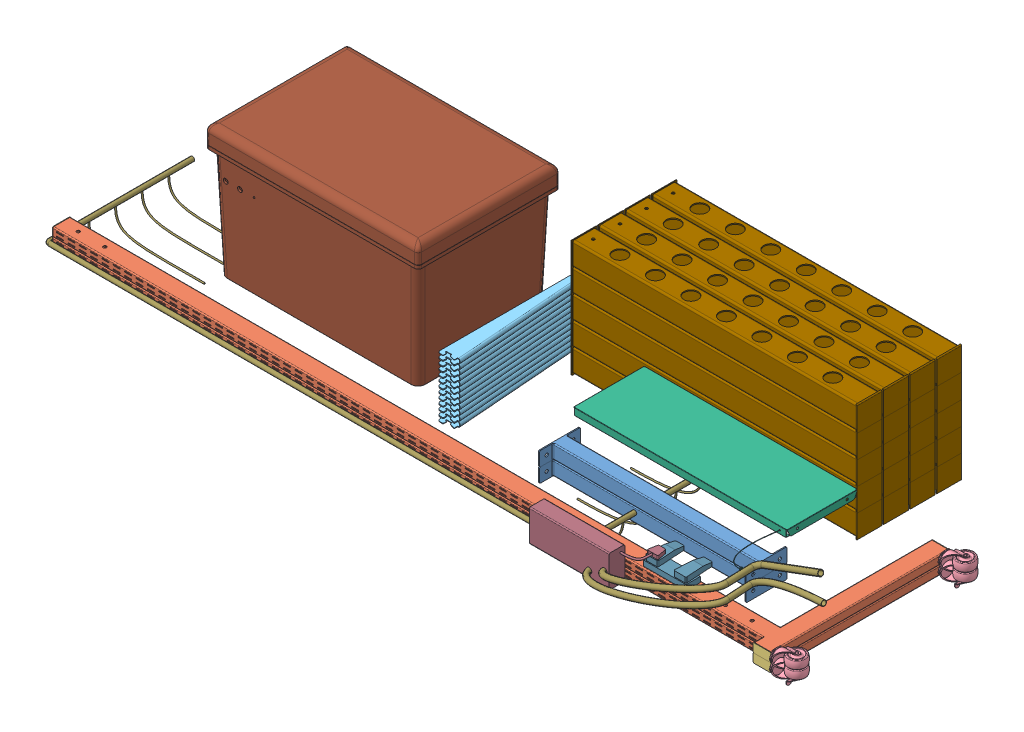
SolidWorks assembly Flat packed, configuration Default. Lengths in mm.
Overall size (2127.7 436.46 799.47).
91 component instances, 17 part files, 246 mates.
Components (placement in the parent):
- TB-600-1: TB-600 [Default] at (652.9227 60 -160.6207) x (-1 0 0) z (0 -1 0) size (585 115 40)
- TB-600-2: TB-600 [Default] at (652.9227 20 -160.6207) x (1 0 0) z (0 -1 0) size (585 115 40)
- TSU-F-L-P-1: TSU-F-L-P [Default] at (1094.8939 31 -50) x (0 1 0) z (0 0 1) size (25 2050 500)
- TSU-F-L-P-2: TSU-F-L-P [Default] at (1094.8939 6 -50) x (0 1 0) z (0 0 1) size (25 2050 500)
- TSU-CAP-1: TSU-CAP [Default] at (1094.7939 5.9 -64.9) x (0 -1 0) z (0 0 -1) size (25.2 50.2 6.5)
- TSU-CAP-2: TSU-CAP [Default] at (1094.7939 30.9 -64.9) x (0 -1 0) z (0 0 -1) size (25.2 50.2 6.5)
- TSU-CAP-3: TSU-CAP [Default] at (-495.0061 31.1 -50.1) x (0 1 0) z (-1 0 0) size (25.2 50.2 6.5)
- TSU-CAP-4: TSU-CAP [Default] at (1094.7939 30.9 -385.1) x (0 1 0) z (0 0 1) size (25.2 50.2 6.5)
- TSU-CAP-5: TSU-CAP [Default] at (-495.0061 6.1 -50.1) x (0 1 0) z (-1 0 0) size (25.2 50.2 6.5)
- TSU-CAP-6: TSU-CAP [Default] at (1094.7939 6.1 -385.1) x (0 1 0) z (0 0 1) size (25.2 50.2 6.5)
- 2834T320_THREADED-STEM SWIVEL CASTER-1: 2834T320_THREADED-STEM SWIVEL CASTER [2834T32] at (1125.8439 31 -462.5) x (0 0 -1) z (0 1 0) size (67.73 101.87 56.07)
- 2834T320_THREADED-STEM SWIVEL CASTER-2: 2834T320_THREADED-STEM SWIVEL CASTER [2834T32] at (1125.8439 6 12.5) x (0 0 -1) z (0 1 0) size (67.73 101.87 56.07)
- 2834T320_THREADED-STEM SWIVEL CASTER-3: 2834T320_THREADED-STEM SWIVEL CASTER [2834T32] at (1125.8439 31 12.5) x (0 0 -1) z (0 1 0) size (67.73 101.87 56.07)
- 2834T320_THREADED-STEM SWIVEL CASTER-4: 2834T320_THREADED-STEM SWIVEL CASTER [2834T32] at (1125.8439 6 -462.5) x (0 0 -1) z (0 1 0) size (67.73 101.87 56.07)
- TSS-600-1: TSS-600 [Default] at (644.4227 20 -318.1207) size (607 37.13 331.17) (hidden)
- TSUB-1: TSUB [Default] at (101.9538 119 -140.6207) x (0 -1 0) z (0 0 -1) size (14.07 50.86 484.03)
- TSUB-2: TSUB [Default] at (101.9538 63 -140.6207) x (0 -1 0) z (0 0 -1) size (14.07 50.86 484.03)
- TSUB-3: TSUB [Default] at (101.9538 77 -140.6207) x (0 -1 0) z (0 0 -1) size (14.07 50.86 484.03)
- TSUB-4: TSUB [Default] at (101.9538 49 -140.6207) x (0 -1 0) z (0 0 -1) size (14.07 50.86 484.03)
- TSS-600-2: TSS-600 [Default] at (644.4227 40 -318.1207) size (607 37.13 331.17) (hidden)
- TSUB-5: TSUB [Default] at (101.9538 147 -140.6207) x (0 -1 0) z (0 0 -1) size (14.07 50.86 484.03)
- TSUB-6: TSUB [Default] at (101.9538 133 -140.6207) x (0 -1 0) z (0 0 -1) size (14.07 50.86 484.03)
- TSS-600-3: TSS-600 [Default] at (644.4227 80 -318.1207) size (607 37.13 331.17) (hidden)
- TSUB-7: TSUB [Default] at (101.9538 7 -140.6207) x (0 -1 0) z (0 0 -1) size (14.07 50.86 484.03)
- TSUB-8: TSUB [Default] at (101.9538 91 -140.6207) x (0 -1 0) z (0 0 -1) size (14.07 50.86 484.03)
- TSS-600-4: TSS-600 [Default] at (644.4227 120 -318.1207) size (607 37.13 331.17)
- TSUB-9: TSUB [Default] at (101.9538 21 -140.6207) x (0 -1 0) z (0 0 -1) size (14.07 50.86 484.03)
- TSUB-10: TSUB [Default] at (101.9538 35 -140.6207) x (0 -1 0) z (0 0 -1) size (14.07 50.86 484.03)
- TSS-600-5: TSS-600 [Default] at (644.4227 60 -318.1207) size (607 37.13 331.17) (hidden)
- TSUB-11: TSUB [Default] at (101.9538 -7 -140.6207) x (0 -1 0) z (0 0 -1) size (14.07 50.86 484.03)
- TSUB-12: TSUB [Default] at (101.9538 105 -140.6207) x (0 -1 0) z (0 0 -1) size (14.07 50.86 484.03)
- TSS-600-6: TSS-600 [Default] at (644.4227 100 -318.1207) size (607 37.13 331.17) (hidden)
- hex bolt gradeab2_bsi-10: hex bolt gradeab2_bsi [BS EN 28765 - M8x1 x 45 x 22-N] at (-858.6061 48.8 -25) x (0 -1 0) z (0.924225 0 -0.381849) size (50.3 15.01 13) (hidden)
- hex bolt gradeab2_bsi-11: hex bolt gradeab2_bsi [BS EN 28765 - M8x1 x 45 x 22-N] at (-783.6061 48.8 -25) x (0 -1 0) z (0.999974 0 0.007224) size (50.3 15.01 13) (hidden)
- hex bolt gradeab2_bsi-12: hex bolt gradeab2_bsi [BS EN 28765 - M8x1 x 45 x 22-N] at (-322.8 60 -198.1207) size (50.3 15.01 13)
- hex bolt gradeab2_bsi-13: hex bolt gradeab2_bsi [BS EN 28765 - M8x1 x 45 x 22-N] at (-322.8 60 -123.1207) size (50.3 15.01 13) (hidden)
- hex bolt gradeab2_bsi-14: hex bolt gradeab2_bsi [BS EN 28765 - M8x1 x 45 x 22-N] at (-322.8 20 -198.1207) size (50.3 15.01 13)
- hex bolt gradeab2_bsi-15: hex bolt gradeab2_bsi [BS EN 28765 - M8x1 x 45 x 22-N] at (-322.8 20 -123.1207) size (50.3 15.01 13) (hidden)
- hex bolt gradeab2_bsi-16: hex bolt gradeab2_bsi [BS EN 28765 - M8x1 x 45 x 22-N] at (1040.3939 48.8 -25) x (0 -1 0) z (-0.924225 0 0.381849) size (50.3 15.01 13) (hidden)
- hex bolt gradeab2_bsi-17: hex bolt gradeab2_bsi [BS EN 28765 - M8x1 x 45 x 22-N] at (856.3064 20 -123.1207) x (-1 0 0) z (0 -0.924225 -0.381849) size (50.3 15.01 13) (hidden)
- hex nut gradec_bsi-1: hex nut gradec_bsi [BS EN 24034 - M8 - N] at (383.6 2067 -25) x (0 0 1) z (-1 0 0) size (13 15.01 7.9) (hidden)
- hex nut gradec_bsi-2: hex nut gradec_bsi [BS EN 24034 - M8 - N] at (383.6 1992 -25) x (0 0 1) z (-1 0 0) size (13 15.01 7.9) (hidden)
- hex nut gradec_bsi-3: hex nut gradec_bsi [BS EN 24034 - M8 - N] at (251.9064 60 -198.1207) x (0 0 -1) z (1 0 0) size (13 15.01 7.9) (hidden)
- hex nut gradec_bsi-4: hex nut gradec_bsi [BS EN 24034 - M8 - N] at (251.9064 60 -123.1207) x (0 0.383049 0.923728) z (1 0 0) size (13 15.01 7.9) (hidden)
- hex nut gradec_bsi-5: hex nut gradec_bsi [BS EN 24034 - M8 - N] at (-281.6 20 -123.1207) x (0 0 -1) z (1 0 0) size (13 15.01 7.9) (hidden)
- hex nut gradec_bsi-6: hex nut gradec_bsi [BS EN 24034 - M8 - N] at (281.6 20 -123.1207) x (0 0 1) z (-1 0 0) size (13 15.01 7.9) (hidden)
- hex nut gradec_bsi-7: hex nut gradec_bsi [BS EN 24034 - M8 - N] at (281.6 168 -25) x (0 0 1) z (-1 0 0) size (13 15.01 7.9) (hidden)
- hex nut gradec_bsi-8: hex nut gradec_bsi [BS EN 24034 - M8 - N] at (-281.6 20 -198.1207) x (0 0 -1) z (1 0 0) size (13 15.01 7.9)
- GB-600-b-1: GB-600-b [Default] at (542.4227 97.5 -600.6207) size (806 70 70)
- GB-600-p-1: GB-600-p [Default] at (0 1106.5 -2988.6404) size (92 218.31 4) (hidden)
- GB-600-p-2: GB-600-p [Default] at (542.4227 1106.5 -675.6207) size (92 218.31 4) (hidden)
- GB-600-b-2: GB-600-b [Default] at (542.4227 97.5 -675.6207) size (806 70 70)
- GB-600-p-3: GB-600-p [Default] at (542.4227 97.5 -450.6207) size (92 218.31 4) (hidden)
- GB-600-b-3: GB-600-b [Default] at (542.4227 97.5 -450.6207) size (806 70 70)
- GB-600-p-4: GB-600-p [Default] at (542.4227 97.5 -525.6207) size (92 218.31 4) (hidden)
- GB-600-b-4: GB-600-b [Default] at (542.4227 97.5 -525.6207) size (806 70 70)
- GB-600-b-5: GB-600-b [Default] at (542.4227 32.5 -450.6207) size (806 70 70)
- GB-600-b-6: GB-600-b [Default] at (542.4227 32.5 -525.6207) size (806 70 70)
- GB-600-b-7: GB-600-b [Default] at (542.4227 32.5 -600.6207) size (806 70 70)
- GB-600-b-8: GB-600-b [Default] at (542.4227 32.5 -675.6207) size (806 70 70)
- GB-600-b-9: GB-600-b [Default] at (542.4227 227.5 -450.6207) size (806 70 70)
- GB-600-b-10: GB-600-b [Default] at (542.4227 227.5 -525.6207) size (806 70 70)
- GB-600-b-11: GB-600-b [Default] at (542.4227 227.5 -600.6207) size (806 70 70)
- GB-600-b-12: GB-600-b [Default] at (542.4227 227.5 -675.6207) size (806 70 70)
- GB-600-p-5: GB-600-p [Default] at (542.4227 227.5 -450.6207) size (92 218.31 4)
- GB-600-p-6: GB-600-p [Default] at (542.4227 227.5 -525.6207) size (92 218.31 4)
- GB-600-p-7: GB-600-p [Default] at (542.4227 227.5 -600.6207) size (92 218.31 4)
- GB-600-p-8: GB-600-p [Default] at (542.4227 227.5 -675.6207) size (92 218.31 4)
- GB-600-p-9: GB-600-p [Default] at (542.4227 1171.5 -675.6207) size (92 218.31 4) (hidden)
- GB-600-p-10: GB-600-p [Default] at (0 1171.5 -2988.6404) size (92 218.31 4) (hidden)
- GB-600-p-11: GB-600-p [Default] at (542.4227 162.5 -525.6207) size (92 218.31 4) (hidden)
- GB-600-p-12: GB-600-p [Default] at (542.4227 162.5 -450.6207) size (92 218.31 4) (hidden)
- GB-600-b-13: GB-600-b [Default] at (542.4227 162.5 -675.6207) size (806 70 70)
- GB-600-b-14: GB-600-b [Default] at (542.4227 162.5 -600.6207) size (806 70 70)
- GB-600-b-15: GB-600-b [Default] at (542.4227 162.5 -525.6207) size (806 70 70)
- GB-600-b-16: GB-600-b [Default] at (542.4227 162.5 -450.6207) size (806 70 70)
- GB-600-p-13: GB-600-p [Default] at (542.4227 292.5 -675.6207) size (92 218.31 4)
- GB-600-p-14: GB-600-p [Default] at (542.4227 292.5 -600.6207) size (92 218.31 4)
- GB-600-p-15: GB-600-p [Default] at (542.4227 292.5 -525.6207) size (92 218.31 4)
- GB-600-p-16: GB-600-p [Default] at (542.4227 292.5 -450.6207) size (92 218.31 4)
- GB-600-b-17: GB-600-b [Default] at (542.4227 292.5 -450.6207) size (806 70 70)
- GB-600-b-18: GB-600-b [Default] at (542.4227 292.5 -525.6207) size (806 70 70)
- GB-600-b-19: GB-600-b [Default] at (542.4227 292.5 -600.6207) size (806 70 70)
- GB-600-b-20: GB-600-b [Default] at (542.4227 292.5 -675.6207) size (806 70 70)
- Part3-1: Part3 [Default] at (-318.2694 320 -342.4034) size (600 370 400)
- Part4-1: Part4 [Default] at origin
- Part5-1: Part5 [Default] at (1094.8939 6 0) x (0 1 0) z (0 0 1) size (241.4 2067.5 489.85)
- Part1-1: Part1 [Default] at (644.4227 82.8692 -318.1207) x (-1 0 0) z (0 -1 0) size (2 2 1357) (hidden)
- Part2-1: Part2 [Default] at (1094.8939 31 -50) x (0 0 -1) z (0 1 0) size (82.56 307.09 97.63)
- ele-1: ele [Default] at (-318.2694 5 -342.4034) x (1 0 0) z (0 1 0) size (624.24 196.22 364.08) (hidden)
- power brick-1: power brick [Default] at (1094.8939 43.5 -50) x (0 0 -1) z (0 1 0) size (82.62 120 30)
Mates (geometry in assembly coordinates):
- Concentric5: concentric anti-aligned: cylinder of TSU-F-L-P-1 through (1094.8939 31 -462.5) axis (1 0 0) radius 5.1; cylinder of 2834T320_THREADED-STEM SWIVEL CASTER-1 through (1106.7939 31 -462.5) axis (-1 0 0) radius 4.7625
- Coincident8: coincident anti-aligned: plane of TSU-F-L-P-1 through (1144.8939 31 -475) normal (1 0 0); plane of 2834T320_THREADED-STEM SWIVEL CASTER-1 through (1144.8939 31 -446.3957) normal (-1 0 0)
- Concentric9: concentric anti-aligned: cylinder of TSU-F-L-P-2 through (1094.8939 6 -462.5) axis (1 0 0) radius 5.1; cylinder of 2834T320_THREADED-STEM SWIVEL CASTER-4 through (1106.7939 6 -462.5) axis (-1 0 0) radius 4.7625
- Parallel4: parallel aligned: plane of TSU-F-L-P-1 through (-905.1061 43.5 -47) normal (0 1 0); plane of 2834T320_THREADED-STEM SWIVEL CASTER-1 through (1161.1023 42.9062 -483.1375) normal (0 1 0)
- Coincident16: coincident anti-aligned: plane of TSU-F-L-P-2 through (1144.8939 6 -475) normal (1 0 0); plane of 2834T320_THREADED-STEM SWIVEL CASTER-4 through (1144.8939 6 -446.3957) normal (-1 0 0)
- Concentric12: concentric anti-aligned: cylinder of TSU-F-L-P-1 through (1094.8939 31 12.5) axis (1 0 0) radius 5.1; cylinder of 2834T320_THREADED-STEM SWIVEL CASTER-3 through (1106.7939 31 12.5) axis (-1 0 0) radius 4.7625
- Coincident17: coincident anti-aligned: plane of TSU-F-L-P-1 through (1144.8939 31 -475) normal (1 0 0); plane of 2834T320_THREADED-STEM SWIVEL CASTER-3 through (1144.8939 31 28.6043) normal (-1 0 0)
- Coincident18: coincident aligned: plane of 2834T320_THREADED-STEM SWIVEL CASTER-1 through (1161.1023 42.9062 -483.1375) normal (0 1 0); plane of 2834T320_THREADED-STEM SWIVEL CASTER-3 through (1161.1023 42.9062 -8.1375) normal (0 1 0)
- Concentric13: concentric anti-aligned: cylinder of TSU-F-L-P-2 through (1094.8939 6 12.5) axis (1 0 0) radius 5.1; cylinder of 2834T320_THREADED-STEM SWIVEL CASTER-2 through (1106.7939 6 12.5) axis (-1 0 0) radius 4.7625
- Coincident19: coincident anti-aligned: plane of TSU-F-L-P-2 through (1144.8939 6 -475) normal (1 0 0); plane of 2834T320_THREADED-STEM SWIVEL CASTER-2 through (1144.8939 6 28.6043) normal (-1 0 0)
- Parallel6: parallel aligned: plane of TSU-F-L-P-2 through (-905.1061 -6.5 -47) normal (0 -1 0); plane of 2834T320_THREADED-STEM SWIVEL CASTER-2 through (1161.1023 -5.9062 -8.1375) normal (0 -1 0)
- Coincident21: coincident anti-aligned: plane of TSU-F-L-P-1 through (-905.1061 20 -25) normal (0 1 0); plane of TSU-CAP-4 through (1094.7939 20 20) normal (0 -1 0)
- Coincident22: coincident anti-aligned: plane of TSU-F-L-P-1 through (1096.3939 40.5 -475) normal (1 0 0); plane of TSU-CAP-4 through (1096.3939 30.9 20) normal (-1 0 0)
- Coincident23: coincident anti-aligned: plane of TSU-F-L-P-1 through (1097.8939 40.5 25) normal (0 0 1); plane of TSU-CAP-4 through (1094.7939 30.9 25) normal (0 0 -1)
- Coincident24: coincident anti-aligned: plane of TSU-F-L-P-2 through (-905.1061 17 -25) normal (0 -1 0); plane of TSU-CAP-6 through (1094.7939 17 20) normal (0 1 0)
- Coincident25: coincident anti-aligned: plane of TSU-F-L-P-2 through (1096.3939 15.5 -475) normal (1 0 0); plane of TSU-CAP-6 through (1096.3939 6.1 20) normal (-1 0 0)
- Coincident26: coincident anti-aligned: plane of TSU-F-L-P-2 through (1097.8939 15.5 25) normal (0 0 1); plane of TSU-CAP-6 through (1094.7939 6.1 25) normal (0 0 -1)
- Coincident27: coincident anti-aligned: plane of TSU-F-L-P-1 through (-905.1061 20 -25) normal (0 1 0); plane of TSU-CAP-2 through (1094.7939 20 -470) normal (0 -1 0)
- Coincident28: coincident anti-aligned: plane of TSU-F-L-P-1 through (1096.3939 40.5 -475) normal (1 0 0); plane of TSU-CAP-2 through (1096.3939 30.9 -470) normal (-1 0 0)
- Coincident29: coincident anti-aligned: plane of TSU-F-L-P-1 through (1097.8939 40.5 -475) normal (0 0 -1); plane of TSU-CAP-2 through (1094.7939 30.9 -475) normal (0 0 1)
- Coincident30: coincident anti-aligned: plane of TSU-F-L-P-2 through (-905.1061 -5 -25) normal (0 1 0); plane of TSU-CAP-1 through (1094.7939 -5 -470) normal (0 -1 0)
- Coincident31: coincident anti-aligned: plane of TSU-F-L-P-2 through (1096.3939 15.5 -475) normal (1 0 0); plane of TSU-CAP-1 through (1096.3939 5.9 -470) normal (-1 0 0)
- Coincident32: coincident anti-aligned: plane of TSU-F-L-P-2 through (1097.8939 15.5 -475) normal (0 0 -1); plane of TSU-CAP-1 through (1094.7939 5.9 -475) normal (0 0 1)
- Coincident33: coincident anti-aligned: plane of TSU-F-L-P-1 through (-905.1061 42 -25) normal (0 -1 0); plane of TSU-CAP-3 through (-900.1061 42 -50.1) normal (0 1 0)
- Coincident34: coincident anti-aligned: plane of TSU-F-L-P-1 through (-905.1061 40.5 -48.5) normal (0 0 1); plane of TSU-CAP-3 through (-900.1061 31.1 -48.5) normal (0 0 -1)
- Coincident35: coincident anti-aligned: plane of TSU-F-L-P-1 through (-905.1061 40.5 -47) normal (-1 0 0); plane of TSU-CAP-3 through (-905.1061 31.1 -50.1) normal (1 0 0)
- Coincident36: coincident anti-aligned: plane of TSU-F-L-P-2 through (-905.1061 17 -25) normal (0 -1 0); plane of TSU-CAP-5 through (-900.1061 17 -50.1) normal (0 1 0)
- Coincident37: coincident anti-aligned: plane of TSU-F-L-P-2 through (-905.1061 15.5 -48.5) normal (0 0 1); plane of TSU-CAP-5 through (-900.1061 6.1 -48.5) normal (0 0 -1)
- Coincident38: coincident anti-aligned: plane of TSU-F-L-P-2 through (-905.1061 15.5 -47) normal (-1 0 0); plane of TSU-CAP-5 through (-905.1061 6.1 -50.1) normal (1 0 0)
- Parallel7: parallel aligned: plane of TSU-F-L-P-2 through (-905.1061 18.5 -47) normal (0 1 0); plane of 2834T320_THREADED-STEM SWIVEL CASTER-4 through (1161.1023 17.9062 -483.1375) normal (0 1 0)
- Coincident90: coincident aligned: plane of TSS-600-4 through (945.4227 120 -418.1207) normal (0 0 -1); plane of TSS-600-6 through (945.4227 100 -418.1207) normal (0 0 -1)
- Coincident91: coincident aligned: plane of TSS-600-3 through (945.4227 80 -418.1207) normal (0 0 -1); plane of TSS-600-6 through (945.4227 100 -418.1207) normal (0 0 -1)
- Coincident93: coincident aligned: plane of TSS-600-3 through (945.4227 80 -418.1207) normal (0 0 -1); plane of TSS-600-5 through (945.4227 60 -418.1207) normal (0 0 -1)
- Coincident94: coincident aligned: plane of TSS-600-2 through (945.4227 40 -418.1207) normal (0 0 -1); plane of TSS-600-5 through (945.4227 60 -418.1207) normal (0 0 -1)
- Coincident95: coincident aligned: plane of TSS-600-1 through (945.4227 20 -418.1207) normal (0 0 -1); plane of TSS-600-2 through (945.4227 40 -418.1207) normal (0 0 -1)
- Concentric15: concentric: cylinder of TSU-F-L-P-1 through (-858.6061 18.5 -25) axis (0 1 0) radius 4.5; cylinder of hex bolt gradeab2_bsi-10 through (-858.6061 48.8 -25) axis (0 1 0) radius 4
- Coincident181: coincident: plane of TSU-F-L-P-1 through (-905.1061 43.5 -47) normal (0 1 0); plane of hex bolt gradeab2_bsi-10 through (-861.4721 43.5 -31.9368) normal (0 -1 0)
- Concentric16: concentric: cylinder of TSU-F-L-P-1 through (-783.6061 18.5 -25) axis (0 1 0) radius 4.5; cylinder of hex bolt gradeab2_bsi-11 through (-783.6061 48.8 -25) axis (0 1 0) radius 4
- Coincident182: coincident: plane of TSU-F-L-P-1 through (-905.1061 43.5 -47) normal (0 1 0); plane of hex bolt gradeab2_bsi-11 through (-783.5518 43.5 -32.5054) normal (0 -1 0)
- Concentric17: concentric: cylinder of TB-600-1 through (945.4227 60 -198.1207) axis (-1 0 0) radius 4.5; cylinder of hex bolt gradeab2_bsi-12 through (-322.8 60 -198.1207) axis (-1 0 0) radius 4
- Coincident183: coincident: plane of TSU-F-L-P-2 through (-905.1061 -6.5 -47) normal (0 -1 0); plane of hex bolt gradeab2_bsi-12 through (-317.5 67.5056 -198.1207) normal (1 0 0)
- Concentric18: concentric: cylinder of TB-600-1 through (945.4227 60 -123.1207) axis (-1 0 0) radius 4.5; cylinder of hex bolt gradeab2_bsi-13 through (-322.8 60 -123.1207) axis (-1 0 0) radius 4
- Coincident184: coincident: plane of TSU-F-L-P-2 through (-905.1061 -6.5 -47) normal (0 -1 0); plane of hex bolt gradeab2_bsi-13 through (-317.5 67.5056 -123.1207) normal (1 0 0)
- Concentric19: concentric: cylinder of TB-600-2 through (360.4227 20 -123.1207) axis (1 0 0) radius 4.5; cylinder of hex bolt gradeab2_bsi-15 through (-322.8 20 -123.1207) axis (-1 0 0) radius 4
- Coincident185: coincident: plane of TSU-F-L-P-2 through (-905.1061 -6.5 -47) normal (0 -1 0); plane of hex bolt gradeab2_bsi-15 through (-317.5 27.5056 -123.1207) normal (1 0 0)
- Concentric20: concentric: cylinder of TB-600-2 through (360.4227 20 -198.1207) axis (1 0 0) radius 4.5; cylinder of hex bolt gradeab2_bsi-14 through (-322.8 20 -198.1207) axis (-1 0 0) radius 4
- Coincident186: coincident: plane of TSU-F-L-P-2 through (-905.1061 -6.5 -47) normal (0 -1 0); plane of hex bolt gradeab2_bsi-14 through (-317.5 27.5056 -198.1207) normal (1 0 0)
- Concentric21: concentric: cylinder of TB-600-2 through (945.4227 20 -123.1207) axis (-1 0 0) radius 4.5; cylinder of hex bolt gradeab2_bsi-17 through (856.3064 20 -123.1207) axis (1 0 0) radius 4
- Coincident187: coincident: plane of TSU-F-L-P-1 through (-905.1061 43.5 -47) normal (0 1 0); plane of hex bolt gradeab2_bsi-17 through (851.0064 22.866 -130.0575) normal (-1 0 0)
- Concentric22: concentric: cylinder of TSU-F-L-P-1 through (1040.3939 16.9 -25) axis (0 1 0) radius 4.5; cylinder of hex bolt gradeab2_bsi-16 through (1040.3939 48.8 -25) axis (0 1 0) radius 4
- Coincident188: coincident: plane of TSU-F-L-P-1 through (-905.1061 43.5 -47) normal (0 1 0); plane of hex bolt gradeab2_bsi-16 through (1043.2599 43.5 -18.0632) normal (0 -1 0)
- Concentric23: concentric: cylinder of hex bolt gradeab2_bsi-10 through (-858.6061 48.8 -25) axis (0 1 0) radius 4; cylinder of hex nut gradec_bsi-1 through (391.5 2067 -25) axis (-1 0 0) radius 3.4
- Coincident189: coincident: plane of TB-600-1 through (363.4227 60 -160.6207) normal (1 0 0); plane of hex nut gradec_bsi-1 through (391.5 2074.5056 -25) normal (1 0 0)
- Concentric24: concentric: cylinder of hex bolt gradeab2_bsi-11 through (-783.6061 48.8 -25) axis (0 1 0) radius 4; cylinder of hex nut gradec_bsi-2 through (391.5 1992 -25) axis (-1 0 0) radius 3.4
- Coincident190: coincident: plane of TB-600-1 through (363.4227 60 -160.6207) normal (1 0 0); plane of hex nut gradec_bsi-2 through (391.5 1999.5056 -25) normal (1 0 0)
- Concentric25: concentric: cylinder of hex bolt gradeab2_bsi-12 through (-322.8 60 -198.1207) axis (-1 0 0) radius 4; cylinder of hex nut gradec_bsi-3 through (244.0064 60 -198.1207) axis (1 0 0) radius 3.4
- Coincident191: coincident: plane of TB-600-1 through (942.4227 60 -160.6207) normal (-1 0 0); plane of hex nut gradec_bsi-3 through (244.0064 67.5056 -198.1207) normal (-1 0 0)
- Concentric26: concentric: cylinder of hex bolt gradeab2_bsi-13 through (-322.8 60 -123.1207) axis (-1 0 0) radius 4; cylinder of hex nut gradec_bsi-4 through (244.0064 60 -123.1207) axis (1 0 0) radius 3.4
- Coincident192: coincident: plane of TB-600-1 through (942.4227 60 -160.6207) normal (-1 0 0); plane of hex nut gradec_bsi-4 through (244.0064 53.0669 -120.2457) normal (-1 0 0)
- Concentric27: concentric: cylinder of hex bolt gradeab2_bsi-15 through (-322.8 20 -123.1207) axis (-1 0 0) radius 4; cylinder of hex nut gradec_bsi-5 through (-289.5 20 -123.1207) axis (1 0 0) radius 3.4
- Coincident193: coincident: plane of TB-600-2 through (363.4227 20 -160.6207) normal (1 0 0); plane of hex nut gradec_bsi-5 through (-289.5 27.5056 -123.1207) normal (-1 0 0)
- Concentric28: concentric: cylinder of hex bolt gradeab2_bsi-14 through (-322.8 20 -198.1207) axis (-1 0 0) radius 4; cylinder of hex nut gradec_bsi-8 through (-289.5 20 -198.1207) axis (1 0 0) radius 3.4
- Coincident194: coincident: plane of TB-600-2 through (363.4227 20 -160.6207) normal (1 0 0); plane of hex nut gradec_bsi-8 through (-289.5 27.5056 -198.1207) normal (-1 0 0)
- Concentric29: concentric: cylinder of hex bolt gradeab2_bsi-17 through (856.3064 20 -123.1207) axis (1 0 0) radius 4; cylinder of hex nut gradec_bsi-6 through (289.5 20 -123.1207) axis (-1 0 0) radius 3.4
- Concentric30: concentric: cylinder of hex bolt gradeab2_bsi-16 through (1040.3939 48.8 -25) axis (0 1 0) radius 4; cylinder of hex nut gradec_bsi-7 through (289.5 168 -25) axis (-1 0 0) radius 3.4
- Coincident195: coincident: plane of TB-600-2 through (942.4227 20 -160.6207) normal (-1 0 0); plane of hex nut gradec_bsi-6 through (289.5 27.5056 -123.1207) normal (1 0 0)
- Coincident196: coincident: plane of TB-600-2 through (942.4227 20 -160.6207) normal (-1 0 0); plane of hex nut gradec_bsi-7 through (289.5 175.5056 -25) normal (1 0 0)
- Concentric31: concentric: cylinder of GB-600-b-1 through (167.4227 62.5 -600.6207) axis (0 1 0) radius 2; cylinder of GB-600-p-1 through (-375 877 -2988.6404) axis (0 1 0) radius 2
- Distance1: distance = 10 mm: plane of GB-600-p-1 through (-375 1087 -2988.6404) normal (0 1 0); plane of GB-600-b-1 through (942.4227 68 -568.1207) normal (0 1 0)
- Concentric32: concentric: cylinder of GB-600-p-2 through (167.4227 877 -675.6207) axis (0 1 0) radius 2; cylinder of GB-600-b-2 through (167.4227 62.5 -675.6207) axis (0 1 0) radius 2
- Distance2: distance = 10 mm: plane of GB-600-p-2 through (167.4227 1087 -675.6207) normal (0 1 0); plane of GB-600-b-2 through (942.4227 68 -643.1207) normal (0 1 0)
- Concentric33: concentric aligned: cylinder of GB-600-p-3 through (167.4227 -132 -450.6207) axis (0 1 0) radius 2; cylinder of GB-600-b-3 through (167.4227 62.5 -450.6207) axis (0 1 0) radius 2
- Distance3: distance = 10 mm aligned: plane of GB-600-p-3 through (167.4227 78 -450.6207) normal (0 1 0); plane of GB-600-b-3 through (942.4227 68 -418.1207) normal (0 1 0)
- Concentric34: concentric aligned: cylinder of GB-600-p-4 through (167.4227 -132 -525.6207) axis (0 1 0) radius 2; cylinder of GB-600-b-4 through (167.4227 62.5 -525.6207) axis (0 1 0) radius 2
- Distance4: distance = 10 mm aligned: plane of GB-600-p-4 through (167.4227 78 -525.6207) normal (0 1 0); plane of GB-600-b-4 through (942.4227 68 -493.1207) normal (0 1 0)
- Coincident206: coincident: plane of GB-600-b-1 through (945.4227 97.5 -600.6207) normal (1 0 0); plane of GB-600-b-4 through (945.4227 97.5 -525.6207) normal (1 0 0)
- Coincident207: coincident: plane of GB-600-b-3 through (945.4227 97.5 -450.6207) normal (1 0 0); plane of GB-600-b-4 through (945.4227 97.5 -525.6207) normal (1 0 0)
- Coincident208: coincident: plane of GB-600-b-1 through (945.4227 97.5 -600.6207) normal (1 0 0); plane of GB-600-b-2 through (945.4227 97.5 -675.6207) normal (1 0 0)
- Distance5: distance = 10 mm: plane of GB-600-b-4 through (942.4227 65 -558.1207) normal (0 0 -1); plane of GB-600-b-1 through (942.4227 65 -568.1207) normal (0 0 1)
- Distance6: distance = 10 mm: plane of GB-600-b-4 through (942.4227 65 -493.1207) normal (0 0 1); plane of GB-600-b-3 through (942.4227 65 -483.1207) normal (0 0 -1)
- Distance7: distance = 10 mm: plane of GB-600-b-1 through (942.4227 65 -633.1207) normal (0 0 -1); plane of GB-600-b-2 through (942.4227 65 -643.1207) normal (0 0 1)
- Distance8: distance = 10 mm: plane of GB-600-b-6 through (942.4227 0 -493.1207) normal (0 0 1); plane of GB-600-b-5 through (942.4227 0 -483.1207) normal (0 0 -1)
- Distance9: distance = 10 mm: plane of GB-600-b-6 through (942.4227 0 -558.1207) normal (0 0 -1); plane of GB-600-b-7 through (942.4227 0 -568.1207) normal (0 0 1)
- Coincident212: coincident: plane of GB-600-b-5 through (945.4227 32.5 -450.6207) normal (1 0 0); plane of GB-600-b-6 through (945.4227 32.5 -525.6207) normal (1 0 0)
- Coincident213: coincident: plane of GB-600-b-7 through (945.4227 32.5 -600.6207) normal (1 0 0); plane of GB-600-b-8 through (945.4227 32.5 -675.6207) normal (1 0 0)
- Coincident214: coincident: plane of GB-600-b-6 through (945.4227 32.5 -525.6207) normal (1 0 0); plane of GB-600-b-7 through (945.4227 32.5 -600.6207) normal (1 0 0)
- Distance10: distance = 10 mm: plane of GB-600-b-7 through (942.4227 0 -633.1207) normal (0 0 -1); plane of GB-600-b-8 through (942.4227 0 -643.1207) normal (0 0 1)
- Coincident215: coincident: plane of GB-600-b-7 through (942.4227 0 -568.1207) normal (0 -1 0); plane of GB-600-b-8 through (942.4227 0 -643.1207) normal (0 -1 0)
- Coincident216: coincident: plane of GB-600-b-6 through (942.4227 0 -493.1207) normal (0 -1 0); plane of GB-600-b-7 through (942.4227 0 -568.1207) normal (0 -1 0)
- Coincident217: coincident: plane of GB-600-b-5 through (942.4227 0 -418.1207) normal (0 -1 0); plane of GB-600-b-6 through (942.4227 0 -493.1207) normal (0 -1 0)
- Concentric35: concentric: cylinder of GB-600-p-2 through (167.4227 877 -675.6207) axis (0 1 0) radius 2; cylinder of GB-600-b-8 through (167.4227 -2.501 -675.6207) axis (0 1 0) radius 4
- Concentric36: concentric aligned: cylinder of GB-600-b-9 through (167.4227 192.5 -450.6207) axis (0 1 0) radius 2; cylinder of GB-600-p-5 through (167.4227 -2 -450.6207) axis (0 1 0) radius 2
- Distance11: distance = 10 mm: plane of GB-600-b-10 through (942.4227 195 -493.1207) normal (0 0 1); plane of GB-600-b-9 through (942.4227 195 -483.1207) normal (0 0 -1)
- Concentric37: concentric: cylinder of GB-600-b-12 through (167.4227 192.5 -675.6207) axis (0 1 0) radius 2; cylinder of GB-600-p-8 through (167.4227 -2 -675.6207) axis (0 1 0) radius 2
- Concentric38: concentric: cylinder of GB-600-b-11 through (167.4227 192.5 -600.6207) axis (0 1 0) radius 2; cylinder of GB-600-p-7 through (167.4227 -2 -600.6207) axis (0 1 0) radius 2
- Distance12: distance = 10 mm: plane of GB-600-p-7 through (167.4227 208 -600.6207) normal (0 1 0); plane of GB-600-b-11 through (942.4227 198 -568.1207) normal (0 1 0)
- Distance13: distance = 10 mm: plane of GB-600-b-10 through (942.4227 195 -558.1207) normal (0 0 -1); plane of GB-600-b-11 through (942.4227 195 -568.1207) normal (0 0 1)
- Concentric39: concentric aligned: cylinder of GB-600-b-10 through (167.4227 192.5 -525.6207) axis (0 1 0) radius 2; cylinder of GB-600-p-6 through (167.4227 -2 -525.6207) axis (0 1 0) radius 2
- Distance14: distance = 10 mm: plane of GB-600-p-8 through (167.4227 208 -675.6207) normal (0 1 0); plane of GB-600-b-12 through (942.4227 198 -643.1207) normal (0 1 0)
- Distance15: distance = 10 mm aligned: plane of GB-600-p-5 through (167.4227 208 -450.6207) normal (0 1 0); plane of GB-600-b-9 through (942.4227 198 -418.1207) normal (0 1 0)
- Distance16: distance = 10 mm aligned: plane of GB-600-p-6 through (167.4227 208 -525.6207) normal (0 1 0); plane of GB-600-b-10 through (942.4227 198 -493.1207) normal (0 1 0)
- Coincident220: coincident: plane of GB-600-b-9 through (945.4227 227.5 -450.6207) normal (1 0 0); plane of GB-600-b-10 through (945.4227 227.5 -525.6207) normal (1 0 0)
- Coincident221: coincident: plane of GB-600-b-11 through (945.4227 227.5 -600.6207) normal (1 0 0); plane of GB-600-b-12 through (945.4227 227.5 -675.6207) normal (1 0 0)
- Coincident222: coincident: plane of GB-600-b-10 through (945.4227 227.5 -525.6207) normal (1 0 0); plane of GB-600-b-11 through (945.4227 227.5 -600.6207) normal (1 0 0)
- Distance17: distance = 10 mm: plane of GB-600-b-11 through (942.4227 195 -633.1207) normal (0 0 -1); plane of GB-600-b-12 through (942.4227 195 -643.1207) normal (0 0 1)
- Coincident223: coincident: plane of GB-600-b-12 through (942.4227 195 -643.1207) normal (0 -1 0); plane of GB-600-b-9 through (942.4227 195 -418.1207) normal (0 -1 0)
- Coincident224: coincident: plane of GB-600-b-9 through (942.4227 195 -418.1207) normal (0 -1 0); plane of GB-600-b-10 through (942.4227 195 -493.1207) normal (0 -1 0)
- Coincident225: coincident: plane of GB-600-b-10 through (942.4227 195 -493.1207) normal (0 -1 0); plane of GB-600-b-11 through (942.4227 195 -568.1207) normal (0 -1 0)
- Coincident226: coincident: plane of GB-600-b-15 through (942.4227 130 -493.1207) normal (0 -1 0); plane of GB-600-b-16 through (942.4227 130 -418.1207) normal (0 -1 0)
- Coincident227: coincident: plane of GB-600-b-14 through (942.4227 130 -568.1207) normal (0 -1 0); plane of GB-600-b-15 through (942.4227 130 -493.1207) normal (0 -1 0)
- Coincident228: coincident: plane of GB-600-b-14 through (945.4227 162.5 -600.6207) normal (1 0 0); plane of GB-600-b-15 through (945.4227 162.5 -525.6207) normal (1 0 0)
- Distance18: distance = 10 mm: plane of GB-600-b-14 through (942.4227 130 -633.1207) normal (0 0 -1); plane of GB-600-b-13 through (942.4227 130 -643.1207) normal (0 0 1)
- Coincident229: coincident: plane of GB-600-b-13 through (942.4227 130 -643.1207) normal (0 -1 0); plane of GB-600-b-16 through (942.4227 130 -418.1207) normal (0 -1 0)
- Concentric40: concentric: cylinder of GB-600-p-10 through (-375 942 -2988.6404) axis (0 1 0) radius 2; cylinder of GB-600-b-14 through (167.4227 127.5 -600.6207) axis (0 1 0) radius 2
- Distance19: distance = 10 mm aligned: plane of GB-600-p-11 through (167.4227 143 -525.6207) normal (0 1 0); plane of GB-600-b-15 through (942.4227 133 -493.1207) normal (0 1 0)
- Concentric41: concentric aligned: cylinder of GB-600-p-12 through (167.4227 -67 -450.6207) axis (0 1 0) radius 2; cylinder of GB-600-b-16 through (167.4227 127.5 -450.6207) axis (0 1 0) radius 2
- Distance20: distance = 10 mm aligned: plane of GB-600-p-12 through (167.4227 143 -450.6207) normal (0 1 0); plane of GB-600-b-16 through (942.4227 133 -418.1207) normal (0 1 0)
- Distance21: distance = 10 mm: plane of GB-600-b-15 through (942.4227 130 -493.1207) normal (0 0 1); plane of GB-600-b-16 through (942.4227 130 -483.1207) normal (0 0 -1)
- Coincident230: coincident: plane of GB-600-b-15 through (945.4227 162.5 -525.6207) normal (1 0 0); plane of GB-600-b-16 through (945.4227 162.5 -450.6207) normal (1 0 0)
- Distance22: distance = 10 mm: plane of GB-600-b-15 through (942.4227 130 -558.1207) normal (0 0 -1); plane of GB-600-b-14 through (942.4227 130 -568.1207) normal (0 0 1)
- Concentric42: concentric: cylinder of GB-600-p-9 through (167.4227 942 -675.6207) axis (0 1 0) radius 2; cylinder of GB-600-b-13 through (167.4227 127.5 -675.6207) axis (0 1 0) radius 2
- Distance23: distance = 10 mm: plane of GB-600-p-9 through (167.4227 1152 -675.6207) normal (0 1 0); plane of GB-600-b-13 through (942.4227 133 -643.1207) normal (0 1 0)
- Distance24: distance = 10 mm: plane of GB-600-p-10 through (-375 1152 -2988.6404) normal (0 1 0); plane of GB-600-b-14 through (942.4227 133 -568.1207) normal (0 1 0)
- Concentric43: concentric aligned: cylinder of GB-600-p-11 through (167.4227 -67 -525.6207) axis (0 1 0) radius 2; cylinder of GB-600-b-15 through (167.4227 127.5 -525.6207) axis (0 1 0) radius 2
- Coincident231: coincident: plane of GB-600-b-13 through (945.4227 162.5 -675.6207) normal (1 0 0); plane of GB-600-b-14 through (945.4227 162.5 -600.6207) normal (1 0 0)
- Coincident233: coincident aligned: plane of GB-600-b-2 through (942.4227 65 -708.1207) normal (0 0 -1); plane of GB-600-b-13 through (942.4227 130 -708.1207) normal (0 0 -1)
- Coincident234: coincident aligned: plane of GB-600-b-2 through (945.4227 97.5 -675.6207) normal (1 0 0); plane of GB-600-b-13 through (945.4227 162.5 -675.6207) normal (1 0 0)
- Coincident236: coincident aligned: plane of GB-600-b-12 through (139.4227 227.5 -675.6207) normal (-1 0 0); plane of GB-600-b-13 through (139.4227 162.5 -675.6207) normal (-1 0 0)
- Coincident237: coincident aligned: plane of GB-600-b-12 through (942.4227 195 -708.1207) normal (0 0 -1); plane of GB-600-b-13 through (942.4227 130 -708.1207) normal (0 0 -1)
- Coincident238: coincident: plane of GB-600-b-17 through (942.4227 260 -418.1207) normal (0 -1 0); plane of GB-600-b-18 through (942.4227 260 -493.1207) normal (0 -1 0)
- Coincident239: coincident: plane of GB-600-b-18 through (942.4227 260 -493.1207) normal (0 -1 0); plane of GB-600-b-19 through (942.4227 260 -568.1207) normal (0 -1 0)
- Coincident240: coincident: plane of GB-600-b-18 through (945.4227 292.5 -525.6207) normal (1 0 0); plane of GB-600-b-19 through (945.4227 292.5 -600.6207) normal (1 0 0)
- Distance25: distance = 10 mm: plane of GB-600-b-19 through (942.4227 260 -633.1207) normal (0 0 -1); plane of GB-600-b-20 through (942.4227 260 -643.1207) normal (0 0 1)
- Coincident241: coincident: plane of GB-600-b-17 through (942.4227 260 -418.1207) normal (0 -1 0); plane of GB-600-b-20 through (942.4227 260 -643.1207) normal (0 -1 0)
- Concentric44: concentric: cylinder of GB-600-p-14 through (167.4227 63 -600.6207) axis (0 1 0) radius 2; cylinder of GB-600-b-19 through (167.4227 257.5 -600.6207) axis (0 1 0) radius 2
- Distance26: distance = 10 mm aligned: plane of GB-600-p-15 through (167.4227 273 -525.6207) normal (0 1 0); plane of GB-600-b-18 through (942.4227 263 -493.1207) normal (0 1 0)
- Concentric45: concentric aligned: cylinder of GB-600-p-16 through (167.4227 63 -450.6207) axis (0 1 0) radius 2; cylinder of GB-600-b-17 through (167.4227 257.5 -450.6207) axis (0 1 0) radius 2
- Distance27: distance = 10 mm aligned: plane of GB-600-p-16 through (167.4227 273 -450.6207) normal (0 1 0); plane of GB-600-b-17 through (942.4227 263 -418.1207) normal (0 1 0)
- Distance28: distance = 10 mm: plane of GB-600-b-18 through (942.4227 260 -493.1207) normal (0 0 1); plane of GB-600-b-17 through (942.4227 260 -483.1207) normal (0 0 -1)
- Coincident242: coincident: plane of GB-600-b-17 through (945.4227 292.5 -450.6207) normal (1 0 0); plane of GB-600-b-18 through (945.4227 292.5 -525.6207) normal (1 0 0)
- Distance29: distance = 10 mm: plane of GB-600-b-18 through (942.4227 260 -558.1207) normal (0 0 -1); plane of GB-600-b-19 through (942.4227 260 -568.1207) normal (0 0 1)
- Concentric46: concentric: cylinder of GB-600-p-13 through (167.4227 63 -675.6207) axis (0 1 0) radius 2; cylinder of GB-600-b-20 through (167.4227 257.5 -675.6207) axis (0 1 0) radius 2
- Distance30: distance = 10 mm: plane of GB-600-p-13 through (167.4227 273 -675.6207) normal (0 1 0); plane of GB-600-b-20 through (942.4227 263 -643.1207) normal (0 1 0)
- Distance31: distance = 10 mm: plane of GB-600-p-14 through (167.4227 273 -600.6207) normal (0 1 0); plane of GB-600-b-19 through (942.4227 263 -568.1207) normal (0 1 0)
- Concentric47: concentric aligned: cylinder of GB-600-p-15 through (167.4227 63 -525.6207) axis (0 1 0) radius 2; cylinder of GB-600-b-18 through (167.4227 257.5 -525.6207) axis (0 1 0) radius 2
- Coincident243: coincident: plane of GB-600-b-19 through (945.4227 292.5 -600.6207) normal (1 0 0); plane of GB-600-b-20 through (945.4227 292.5 -675.6207) normal (1 0 0)
- Coincident245: coincident aligned: plane of GB-600-b-12 through (942.4227 195 -708.1207) normal (0 0 -1); plane of GB-600-b-20 through (942.4227 260 -708.1207) normal (0 0 -1)
- Coincident246: coincident aligned: plane of GB-600-b-12 through (139.4227 227.5 -675.6207) normal (-1 0 0); plane of GB-600-b-20 through (139.4227 292.5 -675.6207) normal (-1 0 0)
- Coincident247: coincident anti-aligned: plane of Part3-1 through (-318.2694 0 -342.4034) normal (0 -1 0)
- Coincident250: coincident: plane of GB-600-b-2 through (945.4227 97.5 -675.6207) normal (1 0 0); plane of GB-600-b-8 through (945.4227 32.5 -675.6207) normal (1 0 0)
- InPlace1: in place: plane of ? through (-305 2113.5 25) normal (0 0 1); plane of ? through (0 0 25) normal (0 0 1); moOrthogonalPlaneRef_w of ? through (-305 2113.5 25) normal (0 0 1); plane of ? through (0 0 25) normal (0 1 0); plane of ? through (-305 2113.5 25) normal (0 0 1); plane of ? through (0 0 25) normal (1 0 0); plane of TSU-F-L-P-2 through (-905.1061 6 0) normal (0 0 1); unknown of Part5-1
- Coincident251: coincident aligned: plane of TSU-F-L-P-2; plane of Part5-1
- Coincident252: coincident aligned: moOrthogonalPlaneRef_w of TSU-F-L-P-2; plane of Part5-1 through (1094.8939 6 0) normal (-1 0 0)
- Coincident253: coincident anti-aligned: moOrthogonalPlaneRef_w of TSU-F-L-P-2 through (6 0 0) axis (-1 0 0); plane of Part5-1 through (1094.8939 6 0) normal (0 1 0)
- InPlace2: in place: plane of ? through (0 2060.8692 30.3916) normal (0 -1 0); plane of ? through (0 2060.8692 0) normal (0 -1 0); plane of ? through (0 2060.8692 30.3916) normal (0 -1 0); plane of ? through (0 2060.8692 0) normal (0 0 -1); plane of ? through (0 2060.8692 30.3916) normal (0 -1 0); plane of ? through (0 2060.8692 0) normal (-1 0 0); plane of TSS-600-4 through (644.4227 82.8692 -88.9468) normal (0 -1 0); unknown of Part1-1
- Coincident251: coincident aligned: plane of TSS-600-4; plane of Part1-1
- Coincident252: coincident aligned: moOrthogonalPlaneRef_w of TSS-600-4 through (644.4227 82.8692 -318.1207) normal (0 0 -1); plane of Part1-1 through (644.4227 82.8692 -318.1207) normal (0 0 -1)
- Coincident253: coincident anti-aligned: moOrthogonalPlaneRef_w of TSS-600-4 through (644.4227 82.8692 -318.1207) normal (1 0 0); plane of Part1-1 through (644.4227 82.8692 -318.1207) normal (-1 0 0)
- InPlace3: in place: plane of ? through (305 113.5 -25) normal (1 0 0); plane of ? through (305 113.5 -25) normal (1 0 0); plane of ? through (305 113.5 -25) normal (1 0 0); plane of ? through (305 113.5 -25) normal (0 1 0); plane of ? through (305 113.5 -25) normal (1 0 0); plane of ? through (305 113.5 -25) normal (0 0 -1); plane of TSU-F-L-P-1 through (1094.8939 31 -50) normal (0 1 0); unknown of Part2-1
- Coincident254: coincident aligned: plane of TSU-F-L-P-1; plane of Part2-1
- Coincident255: coincident aligned: moOrthogonalPlaneRef_w of TSU-F-L-P-1; plane of Part2-1 through (1094.8939 31 -50) normal (-1 0 0)
- Coincident256: coincident anti-aligned: moOrthogonalPlaneRef_w of TSU-F-L-P-1 through (-50 0 0) axis (1 0 0); plane of Part2-1 through (1094.8939 31 -50) normal (0 0 -1)
- InPlace4: in place: plane of ? through (0 5 -225) normal (0 1 0); plane of ? through (0 5 0) normal (0 1 0); plane of ? through (0 5 -225) normal (0 1 0); plane of ? through (0 5 0) normal (0 0 -1); plane of ? through (0 5 -225) normal (0 1 0); plane of ? through (0 5 0) normal (1 0 0); plane of Part3-1 through (-318.2694 5 -342.4034) normal (0 1 0); unknown of ele-1
- Coincident257: coincident aligned: plane of Part3-1; plane of ele-1
- Coincident258: coincident aligned: moOrthogonalPlaneRef_w of Part3-1 through (-318.2694 5 -342.4034) normal (0 0 -1); plane of ele-1 through (-318.2694 5 -342.4034) normal (0 0 -1)
- Coincident259: coincident anti-aligned: moOrthogonalPlaneRef_w of Part3-1 through (-318.2694 5 -342.4034) normal (-1 0 0); plane of ele-1 through (-318.2694 5 -342.4034) normal (1 0 0)
- InPlace5: in place: plane of ? through (317.5 2113.5 -22) normal (1 0 0); plane of ? through (317.5 0 0) normal (1 0 0); plane of ? through (317.5 2113.5 -22) normal (1 0 0); plane of ? through (317.5 0 0) normal (0 1 0); plane of ? through (317.5 2113.5 -22) normal (1 0 0); plane of ? through (317.5 0 0) normal (0 0 -1); plane of TSU-F-L-P-1 through (-905.1061 43.5 -47) normal (0 1 0); unknown of power brick-1
- Coincident260: coincident aligned: plane of TSU-F-L-P-1; plane of power brick-1
- Coincident261: coincident aligned: moOrthogonalPlaneRef_w of TSU-F-L-P-1; plane of power brick-1 through (1094.8939 43.5 -50) normal (-1 0 0)
- Coincident262: coincident anti-aligned: moOrthogonalPlaneRef_w of TSU-F-L-P-1 through (1094.8939 43.5 -50) normal (0 0 1); plane of power brick-1 through (1094.8939 43.5 -50) normal (0 0 -1)
- Parallel11: parallel: plane of GB-600-b-9 through (942.4227 260 -418.1207) normal (0 1 0); plane of GB-600-b-17 through (942.4227 260 -418.1207) normal (0 -1 0)
- Coincident253: coincident: plane of GB-600-b-9 through (942.4227 260 -418.1207) normal (0 1 0); plane of GB-600-b-17 through (942.4227 260 -418.1207) normal (0 -1 0)
- Coincident254: coincident anti-aligned: plane of GB-600-b-12 through (942.4227 260 -643.1207) normal (0 1 0); plane of GB-600-b-20 through (942.4227 260 -643.1207) normal (0 -1 0)
- Coincident256: coincident: plane of GB-600-b-9 through (942.4227 195 -418.1207) normal (0 -1 0); plane of GB-600-b-16 through (942.4227 195 -418.1207) normal (0 1 0)
- Coincident257: coincident anti-aligned: plane of GB-600-b-12 through (942.4227 195 -643.1207) normal (0 -1 0); plane of GB-600-b-13 through (942.4227 195 -643.1207) normal (0 1 0)
- Coincident259: coincident: plane of GB-600-b-3 through (942.4227 130 -418.1207) normal (0 1 0); plane of GB-600-b-16 through (942.4227 130 -418.1207) normal (0 -1 0)
- Parallel15: parallel: plane of GB-600-b-4 through (942.4227 130 -493.1207) normal (0 1 0); plane of GB-600-b-15 through (942.4227 130 -493.1207) normal (0 -1 0)
- Coincident262: coincident: plane of GB-600-b-4 through (942.4227 130 -493.1207) normal (0 1 0); plane of GB-600-b-15 through (942.4227 130 -493.1207) normal (0 -1 0)
- Parallel17: parallel: plane of GB-600-b-10 through (942.4227 195 -493.1207) normal (0 -1 0); plane of GB-600-b-15 through (942.4227 195 -493.1207) normal (0 1 0)
- Coincident264: coincident anti-aligned: plane of GB-600-b-2 through (942.4227 130 -643.1207) normal (0 1 0); plane of GB-600-b-13 through (942.4227 130 -643.1207) normal (0 -1 0)
- Coincident266: coincident: plane of GB-600-b-3 through (942.4227 65 -418.1207) normal (0 -1 0); plane of GB-600-b-5 through (942.4227 65 -418.1207) normal (0 1 0)
- Coincident268: coincident: plane of GB-600-b-4 through (942.4227 65 -493.1207) normal (0 -1 0); plane of GB-600-b-6 through (942.4227 65 -493.1207) normal (0 1 0)
- Coincident270: coincident: plane of GB-600-b-1 through (942.4227 65 -568.1207) normal (0 -1 0); plane of GB-600-b-7 through (942.4227 65 -568.1207) normal (0 1 0)
- Coincident273: coincident: plane of assembly through (0 0 0) normal (0 1 0); plane of GB-600-b-8 through (942.4227 0 -643.1207) normal (0 -1 0); plane of assembly
- Coincident274: coincident: plane of GB-600-b-7 through (942.4227 0 -568.1207) normal (0 -1 0); plane of GB-600-b-8 through (942.4227 0 -643.1207) normal (0 -1 0)
- Coincident275: coincident: plane of GB-600-b-2 through (942.4227 65 -708.1207) normal (0 0 -1); plane of GB-600-b-8 through (942.4227 0 -708.1207) normal (0 0 -1)
- Coincident277: coincident anti-aligned: plane of TSS-600-1 through (945.4227 20 -218.1207) normal (0 1 0); plane of TSS-600-2 through (945.4227 20 -218.1207) normal (0 -1 0)
- Coincident279: coincident anti-aligned: plane of TSS-600-2 through (945.4227 40 -218.1207) normal (0 1 0); plane of TSS-600-5 through (945.4227 40 -418.1207) normal (0 -1 0)
- Coincident281: coincident anti-aligned: plane of TSS-600-3 through (945.4227 60 -418.1207) normal (0 -1 0); plane of TSS-600-5 through (945.4227 60 -218.1207) normal (0 1 0)
- Coincident283: coincident anti-aligned: plane of TSS-600-3 through (945.4227 80 -218.1207) normal (0 1 0); plane of TSS-600-6 through (945.4227 80 -418.1207) normal (0 -1 0)
- Coincident285: coincident: plane of TSS-600-1 through (945.4227 0 -218.1207) normal (0 -1 0); plane of GB-600-b-8 through (942.4227 0 -643.1207) normal (0 -1 0)
- Coincident286: coincident anti-aligned: plane of TSS-600-4 through (945.4227 100 -218.1207) normal (0 -1 0); plane of TSS-600-6 through (945.4227 100 -218.1207) normal (0 1 0)
- Coincident287: coincident aligned: plane of TSS-600-3 through (343.4227 80 -318.1207) normal (-1 0 0); plane of TSS-600-6 through (343.4227 100 -318.1207) normal (-1 0 0)
- Coincident288: coincident: plane of TSS-600-4 through (945.4227 120 -318.1207) normal (1 0 0); plane of GB-600-b-15 through (945.4227 162.5 -525.6207) normal (1 0 0)
- Coincident289: coincident aligned: plane of TSS-600-1 through (343.4227 20 -318.1207) normal (-1 0 0); plane of TSS-600-3 through (343.4227 80 -318.1207) normal (-1 0 0)
- Coincident290: coincident aligned: plane of TSS-600-4 through (343.4227 120 -318.1207) normal (-1 0 0); plane of TSS-600-6 through (343.4227 100 -318.1207) normal (-1 0 0)
- Coincident294: coincident: plane of assembly through (0 0 0) normal (0 1 0); plane of TB-600-2 through (942.4227 0 -180.6207) normal (0 -1 0); plane of assembly
- Coincident296: coincident: plane of assembly through (0 0 0) normal (0 1 0); plane of TSUB-7 through (101.9538 0 -140.6207) normal (0 -1 0); plane of assembly
- Coincident300: coincident anti-aligned: plane of TB-600-1 through (363.4227 40 -140.6207) normal (0 -1 0); plane of TB-600-2 through (942.4227 40 -180.6207) normal (0 1 0)
- Coincident301: coincident aligned: plane of TB-600-1 through (945.4227 60 -160.6207) normal (1 0 0); plane of TB-600-2 through (945.4227 20 -160.6207) normal (1 0 0)
- Coincident302: coincident aligned: plane of TB-600-1 through (363.4227 40 -180.6207) normal (0 0 -1); plane of TB-600-2 through (942.4227 0 -180.6207) normal (0 0 -1)
- Coincident304: coincident anti-aligned: plane of TSUB-7 through (101.9538 0 -140.6207) normal (0 -1 0); plane of TSUB-11 through (101.9538 0 -140.6207) normal (0 1 0)
- Coincident307: coincident anti-aligned: plane of TSUB-7 through (101.9538 14 -140.6207) normal (0 1 0); plane of TSUB-9 through (101.9538 14 -140.6207) normal (0 -1 0)
- Coincident308: coincident aligned: plane of TSUB-7 through (51.9538 0 -140.6207) normal (-1 0 0); plane of TSUB-11 through (51.9538 -14 -140.6207) normal (-1 0 0)
- Coincident309: coincident aligned: plane of TSUB-7 through (51.9538 0 -140.6207) normal (-1 0 0); plane of TSUB-9 through (51.9538 14 -140.6207) normal (-1 0 0)
- Coincident310: coincident aligned: plane of TSU-F-L-P-1 through (-905.1061 31 -50) normal (0 0 -1); plane of TSU-F-L-P-2 through (-905.1061 6 -50) normal (0 0 -1)
- Coincident312: coincident anti-aligned: plane of TSU-F-L-P-1 through (-905.1061 18.5 -47) normal (0 -1 0); plane of TSU-F-L-P-2 through (-905.1061 18.5 -47) normal (0 1 0)
- Coincident313: coincident aligned: plane of TSU-F-L-P-1 through (1144.8939 31 -475) normal (1 0 0); plane of TSU-F-L-P-2 through (1144.8939 6 -475) normal (1 0 0)
- Coincident314: coincident aligned: plane of TSS-600-2 through (343.4227 40 -318.1207) normal (-1 0 0); plane of TSS-600-5 through (343.4227 60 -318.1207) normal (-1 0 0)
- Coincident315: coincident aligned: plane of TSU-F-L-P-1 through (-905.1061 31 0) normal (0 0 1)
- Coincident317: coincident: plane of TSS-600-4 through (945.4227 120 -418.1207) normal (0 0 -1); plane of GB-600-b-17 through (942.4227 260 -418.1207) normal (0 0 1)
- Coincident318: coincident: plane of TB-600-2 through (360.4227 0 -218.1207) normal (0 0 -1); plane of TSS-600-2 through (945.4227 40 -218.1207) normal (0 0 1)
- Coincident321: coincident: plane of TB-600-1 through (945.4227 60 -160.6207) normal (1 0 0); plane of TSS-600-4 through (945.4227 120 -318.1207) normal (1 0 0)
- Coincident323: coincident anti-aligned: plane of TSUB-9 through (101.9538 28 -140.6207) normal (0 1 0); plane of TSUB-10 through (101.9538 28 -140.6207) normal (0 -1 0)
- Coincident324: coincident aligned: plane of TSUB-9 through (51.9538 14 -140.6207) normal (-1 0 0); plane of TSUB-10 through (51.9538 28 -140.6207) normal (-1 0 0)
- Coincident326: coincident aligned: plane of TSS-600-3 through (945.4227 80 -318.1207) normal (1 0 0); plane of TSS-600-5 through (945.4227 60 -318.1207) normal (1 0 0)
- Coincident329: coincident anti-aligned: plane of TSUB-4 through (101.9538 42 -140.6207) normal (0 -1 0); plane of TSUB-10 through (101.9538 42 -140.6207) normal (0 1 0)
- Coincident330: coincident aligned: plane of TSUB-4 through (101.9538 56 -140.6207) normal (0 0 1); plane of TSUB-10 through (101.9538 28 -140.6207) normal (0 0 1)
- Coincident332: coincident anti-aligned: plane of TSUB-2 through (101.9538 56 -140.6207) normal (0 -1 0); plane of TSUB-4 through (101.9538 56 -140.6207) normal (0 1 0)
- Coincident333: coincident aligned: plane of TSUB-2 through (101.9538 70 -140.6207) normal (0 0 1); plane of TSUB-4 through (101.9538 56 -140.6207) normal (0 0 1)
- Coincident334: coincident aligned: plane of TSUB-2 through (51.9538 56 -140.6207) normal (-1 0 0); plane of TSUB-4 through (51.9538 42 -140.6207) normal (-1 0 0)
- Coincident335: coincident: line of TSUB-4 through (51.9538 43.5 -134.6207) axis (0 0 -1); plane of TSUB-10 through (51.9538 28 -140.6207) normal (-1 0 0)
- Coincident337: coincident anti-aligned: plane of TSUB-2 through (101.9538 70 -140.6207) normal (0 1 0); plane of TSUB-3 through (101.9538 70 -140.6207) normal (0 -1 0)
- Coincident338: coincident: line of TSUB-2 through (78.4538 68.5 -140.6207) axis (-1 0 0); plane of TSUB-3 through (101.9538 70 -140.6207) normal (0 0 1)
- Coincident339: coincident aligned: plane of TSUB-9 through (101.9538 14 -140.6207) normal (0 0 1); plane of TSUB-10 through (101.9538 28 -140.6207) normal (0 0 1)
- Coincident340: coincident aligned: plane of TSUB-7 through (101.9538 0 -140.6207) normal (0 0 1); plane of TSUB-9 through (101.9538 14 -140.6207) normal (0 0 1)
- Coincident341: coincident aligned: plane of TSUB-7 through (101.9538 0 -140.6207) normal (0 0 1); plane of TSUB-11 through (101.9538 0 -140.6207) normal (0 0 1)
- Coincident342: coincident aligned: plane of TSUB-2 through (51.9538 56 -140.6207) normal (-1 0 0); plane of TSUB-3 through (51.9538 70 -140.6207) normal (-1 0 0)
- Coincident343: coincident anti-aligned: plane of TSUB-3 through (101.9538 84 -140.6207) normal (0 1 0); plane of TSUB-8 through (101.9538 84 -140.6207) normal (0 -1 0)
- Coincident344: coincident aligned: plane of TSUB-3 through (101.9538 84 -140.6207) normal (0 0 1); plane of TSUB-8 through (101.9538 84 -140.6207) normal (0 0 1)
- Coincident345: coincident aligned: plane of TSUB-3 through (51.9538 70 -140.6207) normal (-1 0 0); plane of TSUB-8 through (51.9538 84 -140.6207) normal (-1 0 0)
- Coincident347: coincident aligned: plane of TB-600-1 through (363.4227 40 -140.6207) normal (0 0 1); plane of TSUB-8 through (101.9538 98 -140.6207) normal (0 0 1)
- Coincident348: coincident: plane of TSUB-11 through (101.9538 -14 -140.6207) normal (0 -1 0); plane of Part2-1 through (1094.8939 -14 -50) normal (0 -1 0)
- Coincident350: coincident anti-aligned: plane of TSUB-8 through (101.9538 98 -140.6207) normal (0 1 0); plane of TSUB-12 through (101.9538 98 -140.6207) normal (0 -1 0)
- Coincident351: coincident anti-aligned: plane of TSUB-1 through (101.9538 112 -140.6207) normal (0 -1 0); plane of TSUB-12 through (101.9538 112 -140.6207) normal (0 1 0)
- Parallel41: parallel anti-aligned: plane of TSUB-1 through (101.9538 126 -140.6207) normal (0 1 0); plane of TSUB-6 through (101.9538 126 -140.6207) normal (0 -1 0)
- Coincident354: coincident anti-aligned: plane of TSUB-1 through (101.9538 126 -140.6207) normal (0 1 0); plane of TSUB-6 through (101.9538 126 -140.6207) normal (0 -1 0)
- Coincident355: coincident aligned: plane of TSUB-8 through (51.9538 84 -140.6207) normal (-1 0 0); plane of TSUB-12 through (51.9538 98 -140.6207) normal (-1 0 0)
- Coincident356: coincident aligned: plane of TSUB-1 through (51.9538 112 -140.6207) normal (-1 0 0); plane of TSUB-12 through (51.9538 98 -140.6207) normal (-1 0 0)
- Coincident357: coincident aligned: plane of TSUB-1 through (101.9538 126 -140.6207) normal (0 0 1); plane of TSUB-6 through (101.9538 126 -140.6207) normal (0 0 1)
- Coincident358: coincident aligned: plane of TSUB-1 through (51.9538 112 -140.6207) normal (-1 0 0); plane of TSUB-6 through (51.9538 126 -140.6207) normal (-1 0 0)
- Coincident360: coincident anti-aligned: plane of TSUB-5 through (101.9538 140 -140.6207) normal (0 -1 0); plane of TSUB-6 through (101.9538 140 -140.6207) normal (0 1 0)
- Coincident361: coincident aligned: plane of TSUB-5 through (51.9538 140 -140.6207) normal (-1 0 0); plane of TSUB-6 through (51.9538 126 -140.6207) normal (-1 0 0)
- Coincident362: coincident aligned: plane of TSUB-5 through (101.9538 154 -140.6207) normal (0 0 1); plane of TSUB-6 through (101.9538 140 -140.6207) normal (0 0 1)
- Coincident363: coincident aligned: plane of TSUB-8 through (101.9538 98 -140.6207) normal (0 0 1); plane of TSUB-12 through (101.9538 98 -140.6207) normal (0 0 1)
- Coincident364: coincident aligned: plane of TSUB-1 through (101.9538 112 -140.6207) normal (0 0 1); plane of TSUB-12 through (101.9538 112 -140.6207) normal (0 0 1)
